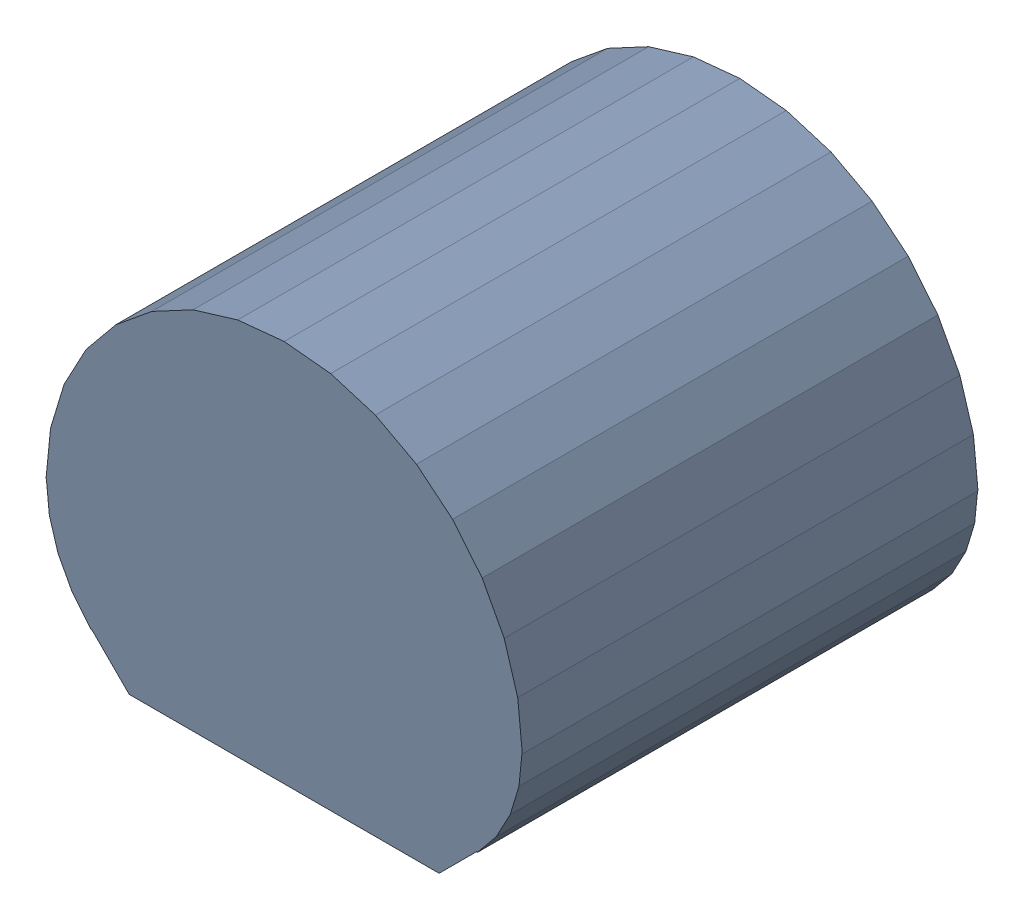
SolidWorks assembly User Library-TO-92_Str_Open_CASCADE_STEP_translator_6.2_1.1, configuration Default. Lengths in mm.
Overall size (5.23 4.2 5).
2 component instances, 1 part files, 0 mates.
Components (placement in the parent):
- User Library-TO-92_Str_547225856-1: User Library-TO-92_Str_547225856 [Default] at (0 0.5113 5) size (5.23 4.2 5)
  - User Library-TO-92_Str_Extruded-1: User Library-TO-92_Str_Extruded [Default] at origin size (5.23 4.2 5)
